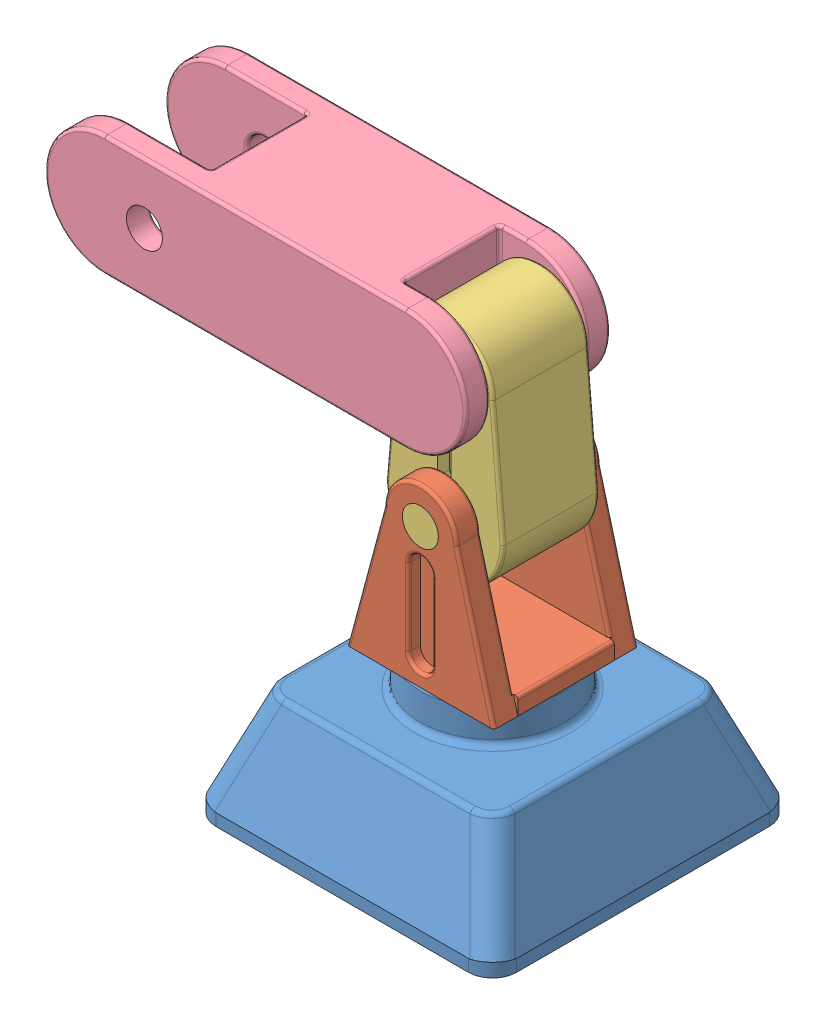
SolidWorks assembly Assem2, configuration Default. Lengths in mm.
Overall size (1110.22 980.21 635).
4 component instances, 4 part files, 9 mates.
Components (placement in the parent):
- Base-1: Base [Default] at (150.4385 206.428 531.7163) size (635 304.8 635)
- anchor-1: anchor [Default] at (150.4385 780.2422 379.3163) size (310.42 446.81 305.51)
- arm-1: arm [Default] at (150.4385 1034.2422 430.1163) size (248.36 479.42 330.2)
- link-1: link [Default] at (-197.7815 1034.2422 379.3163) x (0 1 0) z (0 0 1) size (254 889 304.8)
Mates (geometry in assembly coordinates):
- Concentric1: concentric anti-aligned: cylinder of Base-1 through (150.4385 485.828 531.7163) axis (0 -1 0) radius 127; cylinder of anchor-1 through (150.4385 409.628 531.7163) axis (0 1 0) radius 127
- Coincident2: coincident anti-aligned: plane of Base-1 through (150.4385 409.628 531.7163) normal (0 1 0); plane of anchor-1 through (150.4385 409.628 531.7163) normal (0 -1 0)
- Concentric2: concentric aligned: cylinder of anchor-1 through (150.4385 780.2422 430.1163) axis (0 0 -1) radius 38.1; cylinder of arm-1 through (150.4385 780.2422 684.1163) axis (0 0 -1) radius 38.1
- Coincident4: coincident anti-aligned: plane of anchor-1 through (150.4385 780.2422 633.3163) normal (0 0 -1); plane of arm-1 through (150.4385 780.2422 633.3163) normal (0 0 1)
- Coincident5: coincident anti-aligned: plane of arm-1 through (150.4385 780.2422 633.3163) normal (0 0 1); plane of link-1 through (119.7185 1034.2422 633.3163) normal (0 0 -1)
- Concentric3: concentric aligned: cylinder of arm-1 through (150.4385 1034.2422 430.1163) axis (0 0 1) radius 38.1; cylinder of link-1 through (150.4385 1034.2422 582.5163) axis (0 0 1) radius 38.1
- Parallel1: parallel aligned: plane of Base-1 through (467.9385 181.028 849.2163) normal (1 0 0); plane of anchor-1 through (305.7655 485.828 531.7163) normal (1 0 0)
- Parallel2: parallel anti-aligned: line of anchor-1 through (124.9316 700.1609 677.7663) axis (0 -1 0); line of arm-1 through (164.6456 839.6409 633.3163) axis (0 1 0)
- Perpendicular1: perpendicular: line of arm-1 through (164.6456 839.6409 633.3163) axis (0 1 0); line of link-1 through (119.7185 1154.8922 684.1163) axis (-1 0 0)
